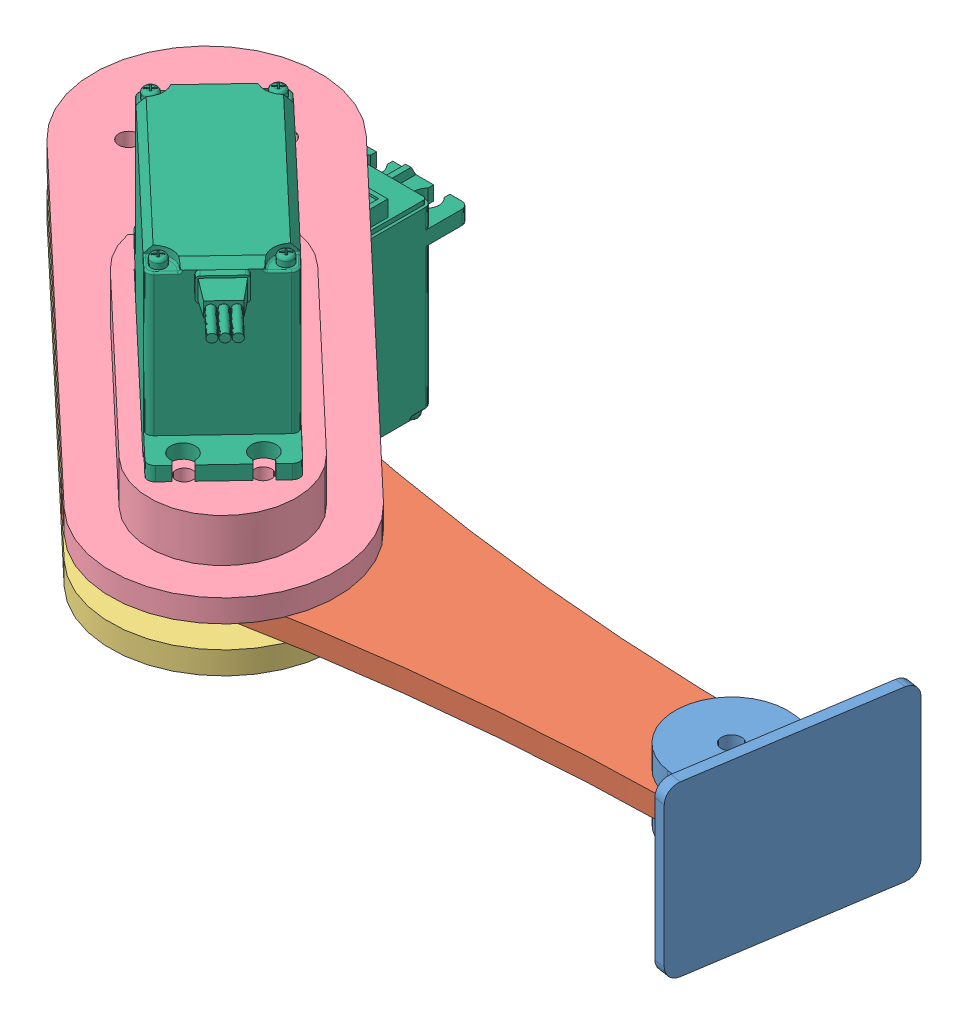
SolidWorks assembly New_Leg, configuration Défaut. Lengths in mm.
Overall size (184.43 89.83 120.1).
7 component instances, 6 part files, 16 mates.
Components (placement in the parent):
- foot-1: foot [Défaut] at (103.1581 -60.55 124.6921) x (0 -1 0) z (0.152369 0 -0.988324) size (30 23 40)
- New_tibia-1: New_tibia [Default] at (0.3981 -59.3375 123.5785) x (0.999953 0 -0.009644) z (-0.009644 0 -0.999953) size (119.89 10.06 40.13)
- New_thigh_2-1: New_thigh_2 [Default] at (-49.8563 -66.2625 75.7966) x (0.725951 0 0.687747) z (-0.687747 0 0.725951) size (120.14 4 40.13)
- New_thigh-1: New_thigh [Default] at (-49.8563 -58.26 75.7966) x (0.725951 0 0.687747) z (-0.687747 0 0.725951) size (120.14 11.7 40.13)
- New_adapter-1: New_adapter [Default] at (-49.8563 -62.26 75.7966) x (0.725951 0 0.687747) z (-0.687747 0 0.725951) size (31.75 17.76 31.75)
- moteur-1: moteur [Défaut] at (-59.7623 -86.9845 65.5096) size (19.88 42.12 58.23)
- moteur-2: moteur [Défaut] at (-0.257 -38.613 109.3123) x (-0.687747 0 0.725951) z (0.725951 0 0.687747) size (19.88 42.12 58.23)
Mates (geometry in assembly coordinates):
- Coaxiale1: concentric anti-aligned: cylinder of New_thigh_2-1 through (-49.8563 -62.8 75.7966) axis (0 -1 0) radius 5.2; cylinder of New_adapter-1 through (-49.8563 -68.76 75.7966) axis (0 1 0) radius 4.627
- Coaxiale2: concentric aligned: circle of New_thigh_2-1; circle of New_adapter-1
- Coïncidente3: coincident anti-aligned: plane of New_thigh_2-1 through (-49.8563 -62.8 75.7966) normal (0 1 0); plane of New_adapter-1 through (-49.8563 -62.8 75.7966) normal (0 -1 0)
- Coaxiale3: concentric anti-aligned: cylinder of New_tibia-1 through (0.3981 -66.9 123.5785) axis (0 1 0) radius 4.625; cylinder of New_thigh_2-1 through (0.3981 -56.8025 123.5785) axis (0 -1 0) radius 5.2
- Coïncidente5: coincident anti-aligned: plane of New_tibia-1 through (0.3981 -62.8 123.5785) normal (0 -1 0); plane of New_thigh_2-1 through (-49.8563 -62.8 75.7966) normal (0 1 0)
- Coaxiale4: concentric aligned: cylinder of New_thigh-1 through (-49.8563 -54.7975 75.7966) axis (0 -1 0) radius 5.2; cylinder of New_adapter-1 through (-49.8563 -51 75.7966) axis (0 -1 0) radius 4.625
- Coïncidente6: coincident anti-aligned: plane of New_thigh-1 through (-49.8563 -58.8 75.7966) normal (0 -1 0); plane of New_adapter-1 through (-49.8563 -58.8 75.7966) normal (0 1 0)
- Coaxiale5: concentric anti-aligned: cylinder of foot-1 through (90.3099 -49.271 122.7113) axis (0 -1 0) radius 1.778; cylinder of New_tibia-1 through (90.3099 -63.561 122.7113) axis (0 1 0) radius 2.54
- Coïncidente7: coincident anti-aligned: plane of foot-1 through (88.7862 -62.8 132.5945) normal (0 1 0); plane of New_tibia-1 through (0.3981 -62.8 123.5785) normal (0 -1 0)
- Coaxiale6: concentric anti-aligned: cylinder of New_adapter-1 through (-49.8563 -60.26 75.7966) axis (0 -1 0) radius 1.375; cylinder of moteur-1 through (-49.8563 -75.2604 75.7966) axis (0 1 0) radius 1.27
- Coïncidente8: coincident anti-aligned: plane of New_adapter-1 through (-49.8563 -68.76 75.7966) normal (0 -1 0); plane of moteur-1 through (-39.9503 -68.76 65.5096) normal (0 1 0)
- Parallèle2: parallel anti-aligned: plane of New_tibia-1 through (0.3981 -58.7975 123.5785) normal (0 1 0); plane of New_thigh-1 through (-49.8563 -58.8 75.7966) normal (0 -1 0)
- Coaxiale7: concentric aligned: circle of New_thigh_2-1; circle of New_thigh-1
- Coaxiale8: concentric aligned: cylinder of New_tibia-1 through (0.3981 -56.8375 123.5785) axis (0 -1 0) radius 4.627; cylinder of moteur-2 through (0.3981 -50.3371 123.5785) axis (0 -1 0) radius 1.27
- Coïncidente10: coincident anti-aligned: plane of New_tibia-1 through (0.3981 -56.8375 123.5785) normal (0 1 0); plane of moteur-2 through (-13.8826 -56.8375 123.6949) normal (0 -1 0)
- Parallèle4: parallel anti-aligned: line of New_thigh-1 through (-63.6566 -54.7975 90.3635) axis (0.725951 0 0.687747); line of moteur-2 through (-27.4354 -44.582 110.8553) axis (-0.725951 0 -0.687747)
